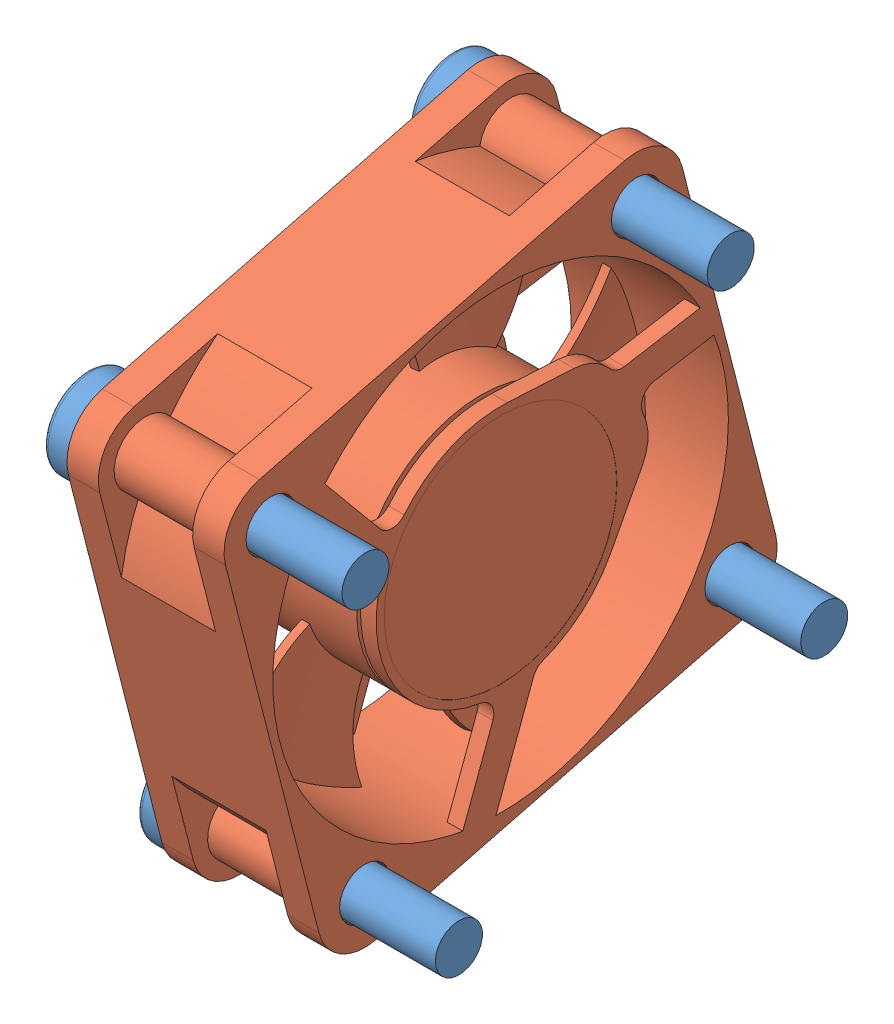
SolidWorks assembly Fan Duct Assembly, configuration Default. Lengths in mm.
Overall size (18.35 38.09 37.92).
6 component instances, 3 part files, 11 mates.
Components (placement in the parent):
- pan head cross recess screw_iso1-1: pan head cross recess screw_iso1 [ISO 7045 - M3 x 16 - Z --- 16N] at (0 -16.5666 -39.5572) size (18.35 5.6 5.6)
- pan head cross recess screw_iso1-2: pan head cross recess screw_iso1 [ISO 7045 - M3 x 16 - Z --- 16N] at (0 6.6834 -33.6044) size (18.35 5.6 5.6)
- pan head cross recess screw_iso1-3: pan head cross recess screw_iso1 [ISO 7045 - M3 x 16 - Z --- 16N] at (0 0.7306 -10.3543) size (18.35 5.6 5.6)
- pan head cross recess screw_iso1-4: pan head cross recess screw_iso1 [ISO 7045 - M3 x 16 - Z --- 16N] at (0 -22.5194 -16.3072) size (18.35 5.6 5.6)
- FAN for Heat Sink (Hotend)-1: FAN for Heat Sink (Hotend) [Default] at (7.4 -7.918 -24.9558) x (0 0.968751 0.248034) z (-1 0 0) size (31.36 31.11 10)
- Fan duct hacked (Hotend)3-1: Fan duct hacked (Hotend)3 [Valor predeterminado] at (27.4 -11.6385 -10.4245) x (1 0 0) z (0 0.968751 0.248034) (suppressed, hidden)
Mates (geometry in assembly coordinates):
- Concentric77: concentric aligned: cylinder of FAN for Heat Sink (Hotend)-1 through (12.4 -16.5666 -39.5572) axis (-1 0 0) radius 1.6; cylinder of pan head cross recess screw_iso-1 through (-25.4 -16.5666 -39.5572) axis (-1 0 0) radius 2.8
- Coincident86: coincident anti-aligned: plane of FAN for Heat Sink (Hotend)-1 through (2.4 2.8927 -6.704) normal (-1 0 0); plane of pan head cross recess screw_iso-1 through (2.4 -15.0666 -39.5572) normal (1 0 0)
- Concentric78: concentric aligned: cylinder of FAN for Heat Sink (Hotend)-1 through (12.4 6.6834 -33.6044) axis (-1 0 0) radius 1.6; cylinder of pan head cross recess screw_iso-2 through (-25.4 6.6834 -33.6044) axis (-1 0 0) radius 2.8
- Coincident87: coincident anti-aligned: plane of FAN for Heat Sink (Hotend)-1 through (2.4 2.8927 -6.704) normal (-1 0 0); plane of pan head cross recess screw_iso-2 through (2.4 8.1834 -33.6044) normal (1 0 0)
- Concentric79: concentric aligned: cylinder of FAN for Heat Sink (Hotend)-1 through (12.4 0.7306 -10.3543) axis (-1 0 0) radius 1.6; cylinder of pan head cross recess screw_iso-3 through (-25.4 0.7306 -10.3543) axis (-1 0 0) radius 2.8
- Coincident88: coincident anti-aligned: plane of FAN for Heat Sink (Hotend)-1 through (2.4 2.8927 -6.704) normal (-1 0 0); plane of pan head cross recess screw_iso-3 through (2.4 2.2306 -10.3543) normal (1 0 0)
- Concentric80: concentric aligned: cylinder of FAN for Heat Sink (Hotend)-1 through (12.4 -22.5194 -16.3072) axis (-1 0 0) radius 1.6; cylinder of pan head cross recess screw_iso-4 through (-25.4 -22.5194 -16.3072) axis (-1 0 0) radius 2.8
- Coincident89: coincident anti-aligned: plane of FAN for Heat Sink (Hotend)-1 through (2.4 2.8927 -6.704) normal (-1 0 0); plane of pan head cross recess screw_iso-4 through (2.4 -21.0194 -16.3072) normal (1 0 0)
- Concentric33: concentric: cylinder of assembly; cone of Fan duct hacked (Hotend)3-1 through (12.4 -16.5666 -39.5572) axis (1 0 0); cylinder of FAN for Heat Sink (Hotend)-1 through (12.4 -16.5666 -39.5572) axis (-1 0 0) radius 1.6
- Concentric34: concentric: cylinder of assembly; cylinder of Fan duct hacked (Hotend)3-1 through (79.2549 0.7306 -10.3543) axis (-1 0 0) radius 1.25; cylinder of FAN for Heat Sink (Hotend)-1 through (12.4 0.7306 -10.3543) axis (-1 0 0) radius 1.6
- Coincident36: coincident: plane of assembly; plane of Fan duct hacked (Hotend)3-1 through (12.4 -26.1698 -14.145) normal (-1 0 0); plane of FAN for Heat Sink (Hotend)-1 through (12.4 2.8927 -6.704) normal (1 0 0)
